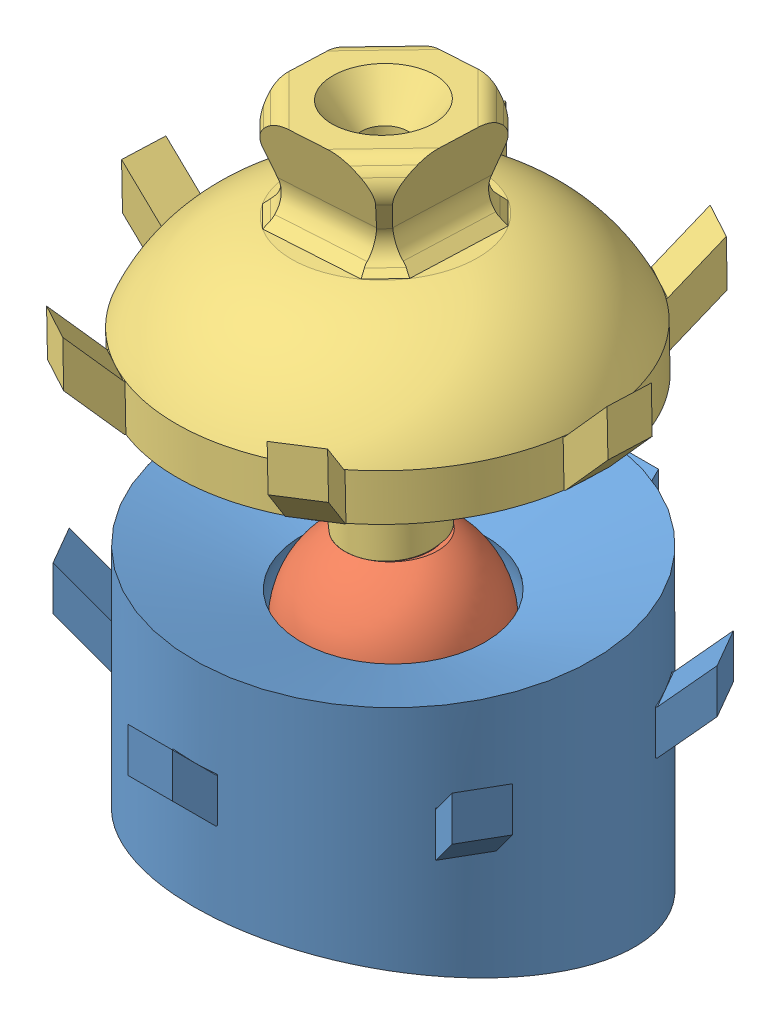
SolidWorks assembly BJL Assembly, configuration Default. Lengths in mm.
Overall size (57.81 78.59 54.9).
3 component instances, 3 part files, 3 mates.
Components (placement in the parent):
- Bottom-1: Bottom [Default] at (26.793 4.7345 42.0057) size (50.05 35.36 54.9)
- Ball-1: Ball [Default] at (26.793 24.7345 42.0057) x (0.995468 0.055206 -0.077432) z (0.075201 0.041402 0.996308) size (20 19.09 20)
- Joint-1: Joint [Default] at (23.677 67.4507 39.8825) x (0.998304 0.058208 -0.00108) z (-0.00108 0.037063 0.999312) size (54.85 51.44 50)
Mates (geometry in assembly coordinates):
- Concentric1: concentric: sphere of Bottom-1; sphere of Ball-1
- Concentric2: concentric: sphere of Bottom-1; sphere of Ball-1
- Parallel2: parallel anti-aligned: plane of Ball-1 through (26.793 24.7345 42.0057) normal (-0.058208 0.997616 -0.037063); plane of Joint-1 through (26.3255 22.0591 41.5689) normal (0.058208 -0.997616 0.037063)
